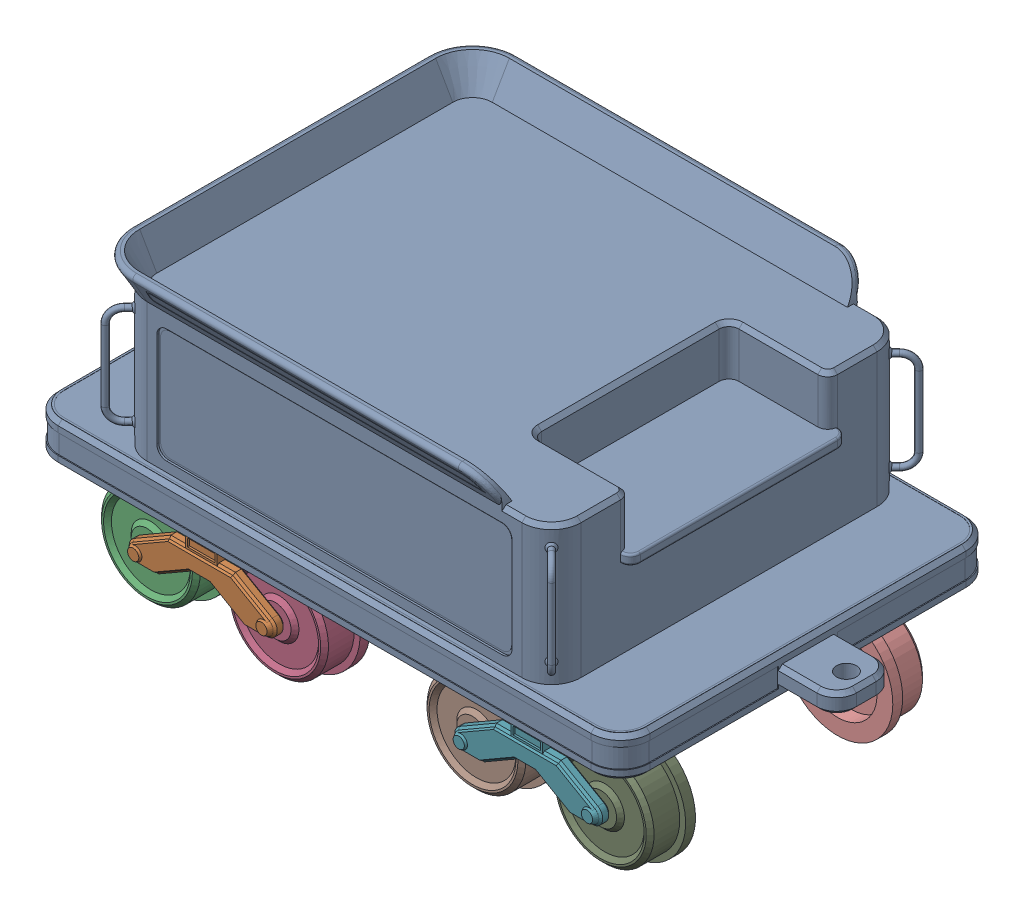
SolidWorks assembly Coal Wagon Assembly, configuration Default. Lengths in mm.
Overall size (329.5 172.68 194.39).
11 component instances, 3 part files, 22 mates.
Components (placement in the parent):
- Coal Wagon-1: Coal Wagon [Default] at (220.1576 47.0008 47.4376) size (329.5 117.39 194.39)
- Coal Wagon Boogie-1: Coal Wagon Boogie [Default] at (220.1576 47.0008 67.4376) size (75 30.11 154)
- Boogie Wheels-1: Boogie Wheels [Default] at (-449.8424 102.0008 197.4376) size (56 56 20)
- Boogie Wheels-2: Boogie Wheels [Default] at (-384.8424 102.0008 197.4376) size (56 56 20)
- Boogie Wheels-3: Boogie Wheels [Default] at (-391.0198 -49.7821 87.4376) x (0.996693 -0.081262 0) z (0 0 -1) size (56 56 20)
- Boogie Wheels-4: Boogie Wheels [Default] at (-456.0198 -49.7821 87.4376) x (0.996693 -0.081262 0) z (0 0 -1) size (56 56 20)
- Coal Wagon Boogie-3: Coal Wagon Boogie [Default] at (385.1576 47.0008 67.4376) size (75 30.11 154)
- Boogie Wheels-5: Boogie Wheels [Default] at (-284.8424 102.0008 197.4376) size (56 56 20)
- Boogie Wheels-6: Boogie Wheels [Default] at (-219.8424 102.0008 197.4376) size (56 56 20)
- Boogie Wheels-7: Boogie Wheels [Default] at (-226.0198 -49.7821 87.4376) x (0.996693 -0.081262 0) z (0 0 -1) size (56 56 20)
- Boogie Wheels-8: Boogie Wheels [Default] at (-291.0198 -49.7821 87.4376) x (0.996693 -0.081262 0) z (0 0 -1) size (56 56 20)
Mates (geometry in assembly coordinates):
- Coincident1: coincident anti-aligned: plane of Coal Wagon-1 through (-12.3424 34.6066 142.4376) normal (0 -1 0); plane of Coal Wagon Boogie-1 through (-12.3424 34.6066 142.4376) normal (0 1 0)
- Concentric1: concentric anti-aligned: cylinder of Coal Wagon-1 through (-12.3424 34.6066 142.4376) axis (0 1 0) radius 25.7069; cylinder of Coal Wagon Boogie-1 through (-12.3424 34.6066 142.4376) axis (0 -1 0) radius 12.5
- Coincident2: coincident anti-aligned: plane of Coal Wagon-1 through (152.6576 34.6066 142.4376) normal (0 -1 0); plane of Coal Wagon Boogie-2 through (152.6576 34.6066 142.4376) normal (0 1 0)
- Concentric2: concentric anti-aligned: cylinder of Coal Wagon-1 through (152.6576 34.6066 142.4376) axis (0 1 0) radius 25.7069; cylinder of Coal Wagon Boogie-2 through (152.6576 34.6066 142.4376) axis (0 -1 0) radius 12.5
- Concentric3: concentric anti-aligned: cylinder of Coal Wagon Boogie-1 through (-44.8424 9.5008 202.4376) axis (0 0 1) radius 4; cylinder of Boogie Wheels-1 through (-44.8424 9.5008 212.4376) axis (0 0 -1) radius 4
- Concentric4: concentric anti-aligned: cylinder of Coal Wagon Boogie-1 through (20.1576 9.5008 202.4376) axis (0 0 1) radius 4; cylinder of Boogie Wheels-2 through (20.1576 9.5008 212.4376) axis (0 0 -1) radius 4
- Coincident3: coincident anti-aligned: plane of Coal Wagon Boogie-1 through (220.1576 47.0008 212.4376) normal (0 0 -1); plane of Boogie Wheels-1 through (-449.8424 102.0008 212.4376) normal (0 0 1)
- Coincident4: coincident anti-aligned: plane of Coal Wagon Boogie-1 through (220.1576 47.0008 212.4376) normal (0 0 -1); plane of Boogie Wheels-2 through (-384.8424 102.0008 212.4376) normal (0 0 1)
- Concentric5: concentric anti-aligned: cylinder of Coal Wagon Boogie-1 through (-44.8424 9.5008 82.4376) axis (0 0 -1) radius 4; cylinder of Boogie Wheels-4 through (-44.8424 9.5008 72.4376) axis (0 0 1) radius 4
- Coincident5: coincident anti-aligned: plane of Coal Wagon Boogie-1 through (220.1576 47.0008 72.4376) normal (0 0 1); plane of Boogie Wheels-4 through (-456.0198 -49.7821 72.4376) normal (0 0 -1)
- Concentric6: concentric anti-aligned: cylinder of Coal Wagon Boogie-1 through (20.1576 9.5008 82.4376) axis (0 0 -1) radius 4; cylinder of Boogie Wheels-3 through (20.1576 9.5008 72.4376) axis (0 0 1) radius 4
- Coincident6: coincident anti-aligned: plane of Coal Wagon Boogie-1 through (220.1576 47.0008 72.4376) normal (0 0 1); plane of Boogie Wheels-3 through (-391.0198 -49.7821 72.4376) normal (0 0 -1)
- Coincident7: coincident anti-aligned: plane of Coal Wagon Boogie-3 through (385.1576 47.0008 72.4376) normal (0 0 1); plane of Boogie Wheels-7 through (-226.0198 -49.7821 72.4376) normal (0 0 -1)
- Coincident8: coincident anti-aligned: plane of Coal Wagon Boogie-3 through (385.1576 47.0008 72.4376) normal (0 0 1); plane of Boogie Wheels-8 through (-291.0198 -49.7821 72.4376) normal (0 0 -1)
- Concentric7: concentric anti-aligned: cylinder of Coal Wagon Boogie-3 through (120.1576 9.5008 82.4376) axis (0 0 -1) radius 4; cylinder of Boogie Wheels-8 through (120.1576 9.5008 72.4376) axis (0 0 1) radius 4
- Concentric8: concentric anti-aligned: cylinder of Coal Wagon Boogie-3 through (185.1576 9.5008 82.4376) axis (0 0 -1) radius 4; cylinder of Boogie Wheels-7 through (185.1576 9.5008 72.4376) axis (0 0 1) radius 4
- Concentric9: concentric anti-aligned: cylinder of Coal Wagon Boogie-3 through (120.1576 9.5008 202.4376) axis (0 0 1) radius 4; cylinder of Boogie Wheels-5 through (120.1576 9.5008 212.4376) axis (0 0 -1) radius 4
- Concentric10: concentric anti-aligned: cylinder of Coal Wagon Boogie-3 through (185.1576 9.5008 202.4376) axis (0 0 1) radius 4; cylinder of Boogie Wheels-6 through (185.1576 9.5008 212.4376) axis (0 0 -1) radius 4
- Coincident9: coincident anti-aligned: plane of Coal Wagon Boogie-3 through (385.1576 47.0008 212.4376) normal (0 0 -1); plane of Boogie Wheels-6 through (-219.8424 102.0008 212.4376) normal (0 0 1)
- Coincident10: coincident anti-aligned: plane of Coal Wagon Boogie-3 through (385.1576 47.0008 212.4376) normal (0 0 -1); plane of Boogie Wheels-5 through (-284.8424 102.0008 212.4376) normal (0 0 1)
- Coincident11: coincident anti-aligned: plane of Coal Wagon-1 through (152.6576 34.6066 142.4376) normal (0 -1 0); plane of Coal Wagon Boogie-3 through (152.6576 34.6066 142.4376) normal (0 1 0)
- Concentric11: concentric anti-aligned: cylinder of Coal Wagon-1 through (152.6576 34.6066 142.4376) axis (0 1 0) radius 25.7069; cylinder of Coal Wagon Boogie-3 through (152.6576 34.6066 142.4376) axis (0 -1 0) radius 12.5
